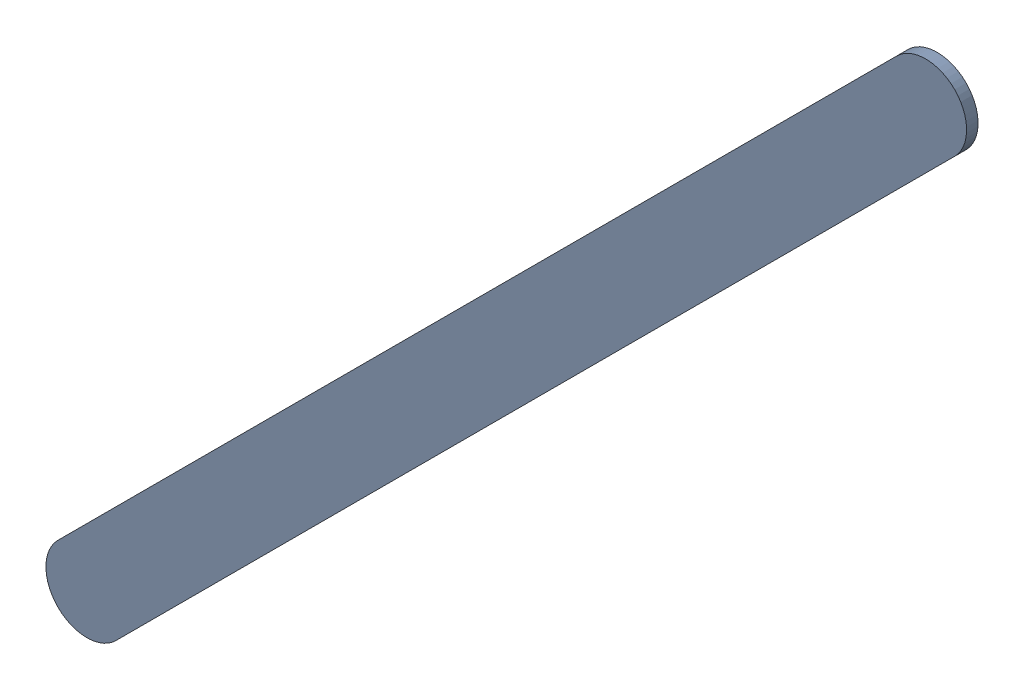
SolidWorks assembly Track (31.8mm,40.7mm)(34.4mm,43.3mm) on Top Layer, configuration Predeterminado. Lengths in mm.
Overall size (2.85 2.85 0.04).
2 component instances, 1 part files, 0 mates.
Components (placement in the parent):
- Track (31.8mm,40.7mm)(34.4mm,43.3mm) on Top Layer-1-1: Track (31.8mm,40.7mm)(34.4mm,43.3mm) on Top Layer-1 [Predeterminado] at (-68.317 -44.187 -0.0457) size (2.85 2.85 0.04)
  - Track (31.8mm,40.7mm)(34.4mm,43.3mm) on Top Layer-Part-1-1: Track (31.8mm,40.7mm)(34.4mm,43.3mm) on Top Layer-Part-1 [Predeterminado] at origin size (2.85 2.85 0.04)
